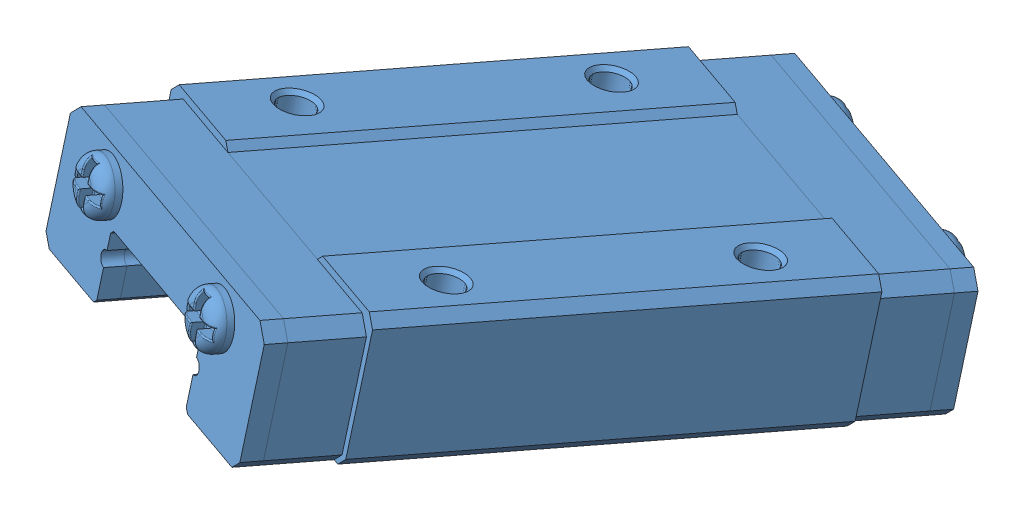
SolidWorks assembly MGN12H-300, configuration 預設. Lengths in mm.
Overall size (42.36 20.49 55.82).
2 component instances, 2 part files, 3 mates.
Components (placement in the parent):
- MGN12H-1: MGN12H [Default] at (24.9755 -23.6401 269.2579) x (0.939115 0.024026 0.342762) z (-0.340094 0.207203 0.91728) size (27 10 48.55)
- MGNR12-1: MGNR12 [Default] at (68.1159 -45.8921 152.6195) x (0.939115 0.024026 0.342762) z (-0.340094 0.207203 0.91728) (suppressed, hidden)
Mates (geometry in assembly coordinates):
- 重合/共線/共點1: coincident anti-aligned: plane of MGN12H-1 through (9.7339 -9.8685 292.5473) normal (-0.048983 -0.978003 0.202758); plane of MGNR12-1 through (-39.351 20.0365 424.936) normal (0.048983 0.978003 -0.202758)
- 同軸心1: concentric anti-aligned: circle of MGN12H-1; circle of MGNR12-1
- 同軸心2: concentric anti-aligned: circle of MGN12H-1; circle of MGNR12-1
